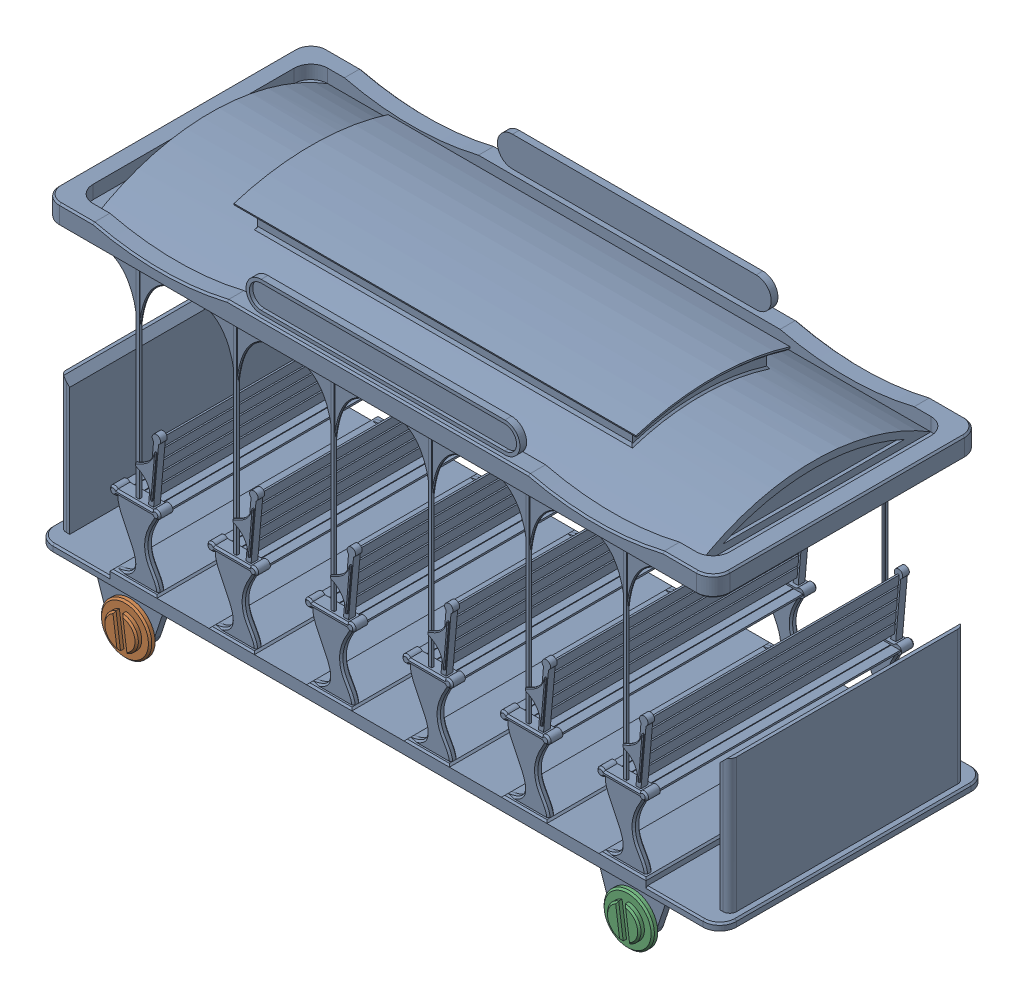
SolidWorks assembly Streetcar Assembly, configuration Default. Lengths in mm.
Overall size (204 120.96 84).
3 component instances, 2 part files, 5 mates.
Components (placement in the parent):
- Streetcar-1: Streetcar [Default] at (22.652 90.7 59.4851) size (204 115.5 80)
- Streetcar Wheels-1: Streetcar Wheels [Default] at (-52.348 31.7 138.4851) x (-0.990555 -0.137119 0) z (0 0 1) size (15 15 84)
- Streetcar Wheels-2: Streetcar Wheels [Default] at (97.652 31.7 138.4851) x (-0.990555 -0.137119 0) z (0 0 1) size (15 15 84)
Mates (geometry in assembly coordinates):
- Concentric1: concentric aligned: cylinder of Streetcar-1 through (-52.348 31.7 136.4851) axis (0 0 1) radius 2; cylinder of Streetcar Wheels-1 through (-52.348 31.7 99.4851) axis (0 0 1) radius 2
- Concentric2: concentric aligned: cylinder of Streetcar-1 through (97.652 31.7 136.4851) axis (0 0 1) radius 2; cylinder of Streetcar Wheels-2 through (97.652 31.7 99.4851) axis (0 0 1) radius 2
- Coincident1: coincident anti-aligned: plane of Streetcar-1 through (22.652 90.7 138.4851) normal (0 0 1); plane of Streetcar Wheels-2 through (97.652 31.7 138.4851) normal (0 0 -1)
- Coincident2: coincident anti-aligned: plane of Streetcar-1 through (22.652 90.7 138.4851) normal (0 0 1); plane of Streetcar Wheels-1 through (-52.348 31.7 138.4851) normal (0 0 -1)
- GearMate1: gear = 15 : 15 mm: cylinder of Streetcar Wheels-2 through (97.652 31.7 58.9851) axis (0 0 1) radius 7.5; cylinder of Streetcar Wheels-1 through (-52.348 31.7 58.9851) axis (0 0 1) radius 7.5
